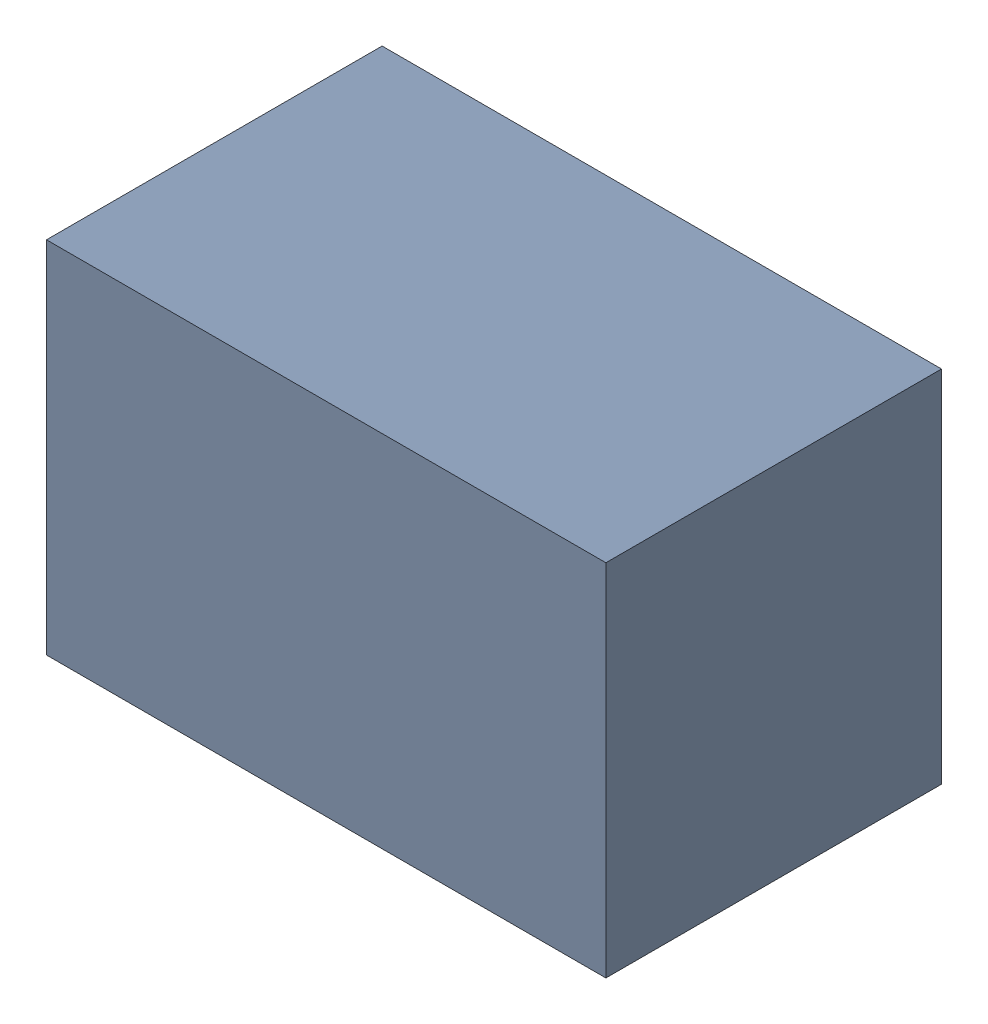
SolidWorks assembly C42, configuration Default. Lengths in mm.
Overall size (2.1 1.35 1.26).
2 component instances, 1 part files, 0 mates.
Components (placement in the parent):
- 407985824-1: 407985824 [Default] at (30.988 62.5856 0.0127) size (2.1 1.35 1.26)
  - Extruded_2-1: Extruded_2 [Default] at origin size (2.1 1.35 1.26)
